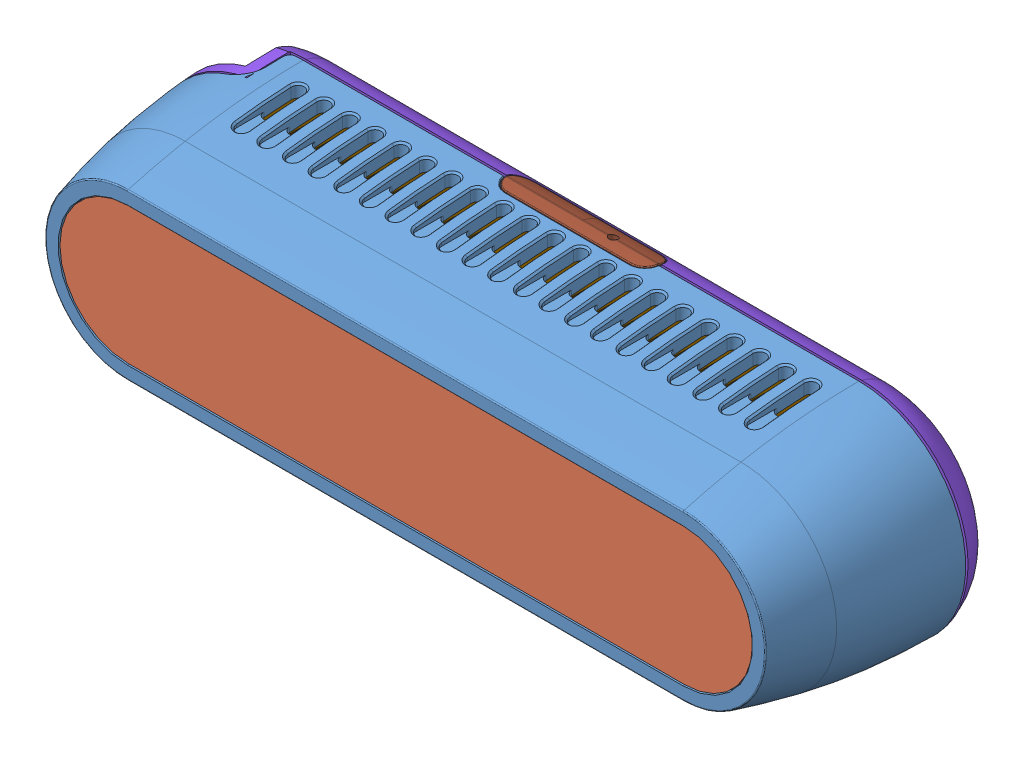
SolidWorks assembly Intel_RealSense_Depth_Camera_D435, configuration Default. Lengths in mm.
Overall size (90.48 26.3 25.07).
49 component instances, 31 part files, 0 mates.
Components (placement in the parent):
- 000_TA_DS5_DEV_KIT_AWG_RGB_ASM__ASM-1: 000_TA_DS5_DEV_KIT_AWG_RGB_ASM__ASM [Default] at origin size (90.48 26.3 25.07)
  - FRONT_COVER_ALUMINUM_AWG_W_RGB_-1: FRONT_COVER_ALUMINUM_AWG_W_RGB_ [Default] at origin size (89.82 25.51 20.61)
  - LENS_COVER_SUBASSY_AWG_W_RGB_AS_ASM-1: LENS_COVER_SUBASSY_AWG_W_RGB_AS_ASM [Default] at origin size (80.99 15.99 0.7)
    - LENS_MASK_AWG_RGB_ASM_6_ASM-1: LENS_MASK_AWG_RGB_ASM_6_ASM [Default] at origin size (80.99 15.99 0.57)
      - LENS_COVER_AWG_RGB_44-1: LENS_COVER_AWG_RGB_44 [Default] at origin size (80.99 15.99 0.55)
      - MASK_LENS_AWG_RGB_43-1: MASK_LENS_AWG_RGB_43 [Default] at origin size (80.39 15.39 0.03)
    - ADHESIVE_LENS_AWG_RGB_23-1: ADHESIVE_LENS_AWG_RGB_23 [Default] at origin size (80.39 15.39 0.13)
  - FOAM_ISOLATION_CARRIER_AWG_RGB__ASM-1: FOAM_ISOLATION_CARRIER_AWG_RGB__ASM [Default] at origin size (80.67 15.67 0.88)
    - AWG_FOAM_FRONT_BEZEL_RIGHT_49-1: AWG_FOAM_FRONT_BEZEL_RIGHT_49 [Default] at origin size (80.67 15.67 0.53)
    - AWG_ADHESIVE_FRONT_BEZEL_1_18-1: AWG_ADHESIVE_FRONT_BEZEL_1_18 [Default] at origin size (80.67 15.67 0.05)
    - AWG_STIFFENER_FRONT_BEZEL_1_18-1: AWG_STIFFENER_FRONT_BEZEL_1_18 [Default] at (0 0 0.25) size (80.67 15.67 0.25)
    - AWG_ADHESIVE_FRONT_BEZEL_1_18-2: AWG_ADHESIVE_FRONT_BEZEL_1_18 [Default] at (0 0 0.3) size (80.67 15.67 0.05)
  - CAMERA_MOD_DS5_AWG_ASM_46_ASM-1: CAMERA_MOD_DS5_AWG_ASM_46_ASM [Default] at origin size (70.7 14.71 10.52)
    - MODULE_CAMERA_DS5_AWG_RGB_6-1: MODULE_CAMERA_DS5_AWG_RGB_6 [Default] at (-32.5 0 -11.47) size (70.7 14.01 10.52)
    - 20708-050EC_20709-050EC_MATIN_1_ASM-1: 20708-050EC_20709-050EC_MATIN_1_ASM [Default] at (6.878 -3.605 -10.01) x (1 0 0) z (0 -1 0) size (10.92 0.67 2.3)
      - 20709-050E_RECE_ASSY_3-1: 20709-050E_RECE_ASSY_3 [Default] at origin size (10.92 0.67 2.3)
    - B2B_BRACKET_AWG_W_RGB_1-1: B2B_BRACKET_AWG_W_RGB_1 [Default] at (2.7 -7 -3.11) size (16.82 8 5.57)
    - LABEL_CAMERA_DS5_AWG_ASM_40_ASM-1: LABEL_CAMERA_DS5_AWG_ASM_40_ASM [Default] at origin size (63.7 14.71 1.8)
      - LABEL_CAMERA_DS5_AWG_36-1: LABEL_CAMERA_DS5_AWG_36 [Default] at origin size (63.7 14.71 1.8)
      - ADHESIVE_LABEL_CAMERA_DS5_AWG_2-1: ADHESIVE_LABEL_CAMERA_DS5_AWG_2 [Default] at origin size (63.7 13 0.05)
  - DS5_RGB_MODULE_ASM_13_ASM-1: DS5_RGB_MODULE_ASM_13_ASM [Default] at (32.5 0 -3.5582) size (16.48 16.2 12.11)
    - AWG_RGB_CAMERA_MERGED_5-1: AWG_RGB_CAMERA_MERGED_5 [Default] at origin size (8 5.7 2)
    - AWG_RGB_CAMERA_5-1: AWG_RGB_CAMERA_5 [Default] at origin size (4.9 4.9 2)
    - AWG_RGB_CAMERA_BOARD_22-1: AWG_RGB_CAMERA_BOARD_22 [Default] at origin size (11.5 8.8 1.15)
    - AWG_RGB_CAMERA_FLEX_SHEETMETAL_-1: AWG_RGB_CAMERA_FLEX_SHEETMETAL_ [Default] at origin size (14.58 8.8 8.14)
    - BRACKET_RGB_MODULE_AWG_W_RGB_46-1: BRACKET_RGB_MODULE_AWG_W_RGB_46 [Default] at origin size (13.9 16.2 4.21)
  - HEATSINK_AWG_W_RGB_24-1: HEATSINK_AWG_W_RGB_24 [Default] at origin size (84.95 23.2 15.34)
  - PASTE_THERMAL_IR_AWG_W_RGB_7-1: PASTE_THERMAL_IR_AWG_W_RGB_7 [Default] at origin size (12.17 8 0.1)
  - SCREW_M1-6_4L_4-1: SCREW_M1-6_4L_4 [Default] at (28.2 6.3 -7.7832) size (3.2 3.2 5.3)
  - SCREW_M1-6_4L_4-2: SCREW_M1-6_4L_4 [Default] at (33.9 -6.3 -7.7832) size (3.2 3.2 5.3)
  - SCREW_M1-6_4L_4-3: SCREW_M1-6_4L_4 [Default] at (-41.601 0 -13.72) size (3.2 3.2 5.3)
  - SCREW_M1-6_4L_4-4: SCREW_M1-6_4L_4 [Default] at (26.599 0 -13.72) size (3.2 3.2 5.3)
  - FPC_DS5_DK_ASIC_AWG_STEREO_IM_1_ASM-1: FPC_DS5_DK_ASIC_AWG_STEREO_IM_1_ASM [Default] at origin size (29.07 9.25 12.16)
    - AWG_ASIC_FLEX_33-1: AWG_ASIC_FLEX_33 [Default] at origin size (29.07 9.25 11.16)
    - AWG_ASIC_BACKER_1_77-1: AWG_ASIC_BACKER_1_77 [Default] at (0 0 0.2) size (12 4 0.5)
    - ID_50_PIN_20709-050EC_PAD_4-1: ID_50_PIN_20709-050EC_PAD_4 [Default] at (2.68 -3.605 -9.31) x (1 0 0) z (0 0 -1) size (10.92 2.3 0.67)
    - AWG_ASIC_BACKER_2_84-1: AWG_ASIC_BACKER_2_84 [Default] at (0 0 -0.2) size (12 4.5 0.5)
    - 20708-050E_PLUG_ASSY_3-1: 20708-050E_PLUG_ASSY_3 [Default] at (23.95 -5.75 -19.37) x (1 0 0) z (0 1 0) size (10.06 0.56 1.8)
  - REAR_COVER_SUBASSY_AWG_W_RGB_AS_ASM-1: REAR_COVER_SUBASSY_AWG_W_RGB_AS_ASM [Default] at origin size (90.48 26.3 10.45)
    - REAR_COVER_ALUMINUM_AWG_RGB_121-1: REAR_COVER_ALUMINUM_AWG_RGB_121 [Default] at origin size (90.48 26.3 10.45)
    - MAGNET_9-1: MAGNET_9 [Default] at (7.25 9.3 -20.82) x (-1 0 0) z (0 1 0) size (1.6 1.6 1.6)
    - MAGNET_9-2: MAGNET_9 [Default] at (-7.25 9.3 -20.82) x (-1 0 0) z (0 1 0) size (1.6 1.6 1.6)
  - SCREW_TORX_M2_X_5L_6-1: SCREW_TORX_M2_X_5L_6 [Default] at (-39.4 -4.8 -17.12) x (-1 0 0) z (0 0 -1) size (4 4 5.08)
  - SCREW_TORX_M2_X_5L_6-2: SCREW_TORX_M2_X_5L_6 [Default] at (-39.4 4.8 -17.12) x (-1 0 0) z (0 0 -1) size (4 4 5.08)
  - AUX_COVER_SUBASSY_AWG_W_RGB_ASM_ASM-1: AUX_COVER_SUBASSY_AWG_W_RGB_ASM_ASM [Default] at origin size (17.91 4.42 3.42)
    - AUX_COVER_ALUMINUM_AWG_W_RGB_61-1: AUX_COVER_ALUMINUM_AWG_W_RGB_61 [Default] at origin size (17.91 4.42 3.42)
    - PIN_STEEL_ZINC_PLATED_11-1: PIN_STEEL_ZINC_PLATED_11 [Default] at (7.25 10.95 -20.82) x (1 0 0) z (0 -1 0) size (1.6 1.6 1.6)
    - PIN_STEEL_ZINC_PLATED_11-2: PIN_STEEL_ZINC_PLATED_11 [Default] at (-7.25 10.95 -20.82) x (1 0 0) z (0 -1 0) size (1.6 1.6 1.6)
  - BARCODE_AWG_8-1: BARCODE_AWG_8 [Default] at (0 -11.3331 -6.6932) x (1 0 0) z (0 0.974201 -0.225683) size (40 4 0.09)
